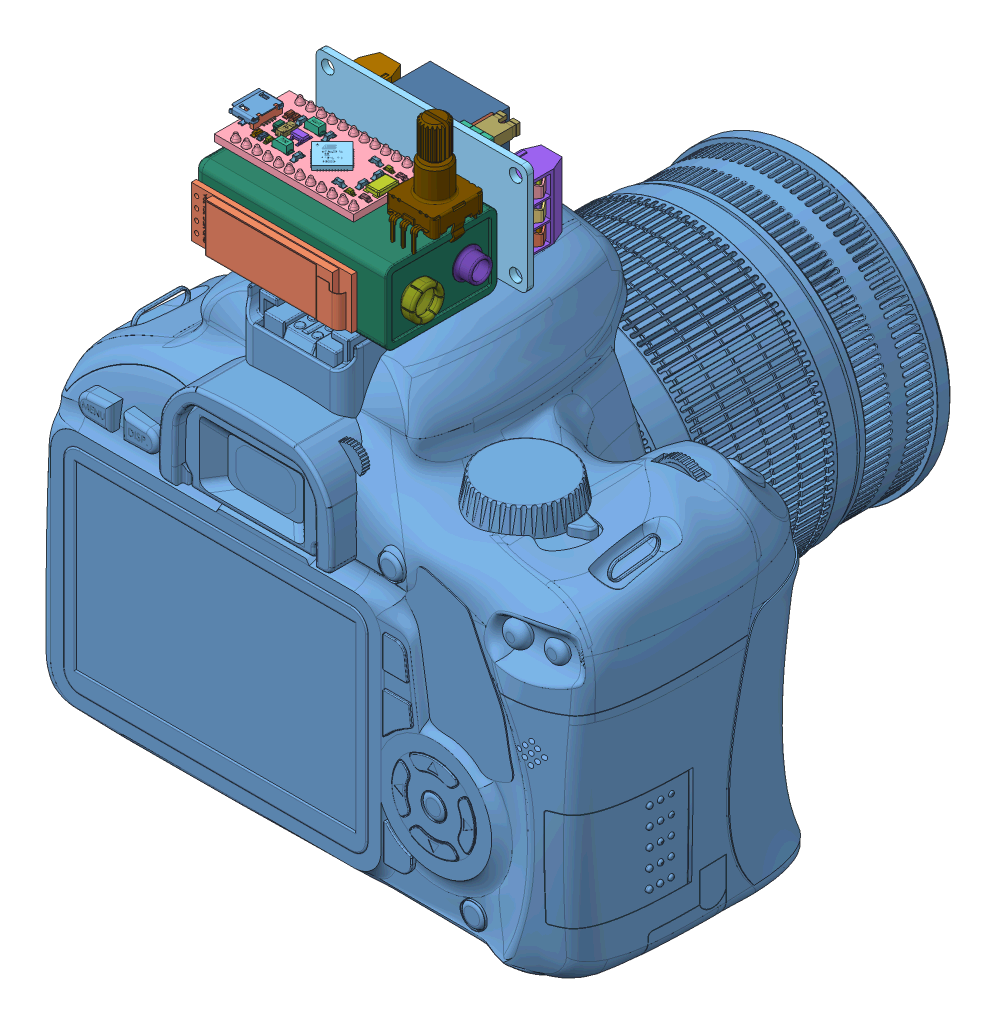
SolidWorks assembly Intervalometer_V1, configuration Default. Lengths in mm.
Overall size (132.46 153.58 139.83).
93 component instances, 74 part files, 0 mates.
Components (placement in the parent):
- ARDUINO PRO MICRO^Intervalometer_V1-1: ARDUINO PRO MICRO^Intervalometer_V1 [Default] at (-2.2476 67.1806 24.4851) size (34.59 4.25 17.78) (virtual)
  - micro usb^ARDUINO PRO MICRO_Intervalometer_V1-1: micro usb^ARDUINO PRO MICRO_Intervalometer_V1 [Default] at (-4.75 1.85 -7.62) x (0 0 1) z (-1 0 0) size (8 3.25 5.93) (virtual)
    - micro usb shell^micro usb_ARDUINO PRO MICRO_Intervalometer_V1-1: micro usb shell^micro usb_ARDUINO PRO MICRO_Intervalometer_V1 [Default] at origin size (8 2.95 5.63) (virtual)
    - micro usb internal^micro usb_ARDUINO PRO MICRO_Intervalometer_V1-1: micro usb internal^micro usb_ARDUINO PRO MICRO_Intervalometer_V1 [Default] at (0 -0.25 0) size (6.9 2.9 4) (virtual)
    - micro usb contact^micro usb_ARDUINO PRO MICRO_Intervalometer_V1-1: micro usb contact^micro usb_ARDUINO PRO MICRO_Intervalometer_V1 [Default] at (1.3 -0.25 -0.1) size (0.2 1.3 4.4) (virtual)
    - micro usb contact^micro usb_ARDUINO PRO MICRO_Intervalometer_V1-2: micro usb contact^micro usb_ARDUINO PRO MICRO_Intervalometer_V1 [Default] at (0.65 -0.25 -0.1) size (0.2 1.3 4.4) (virtual)
    - micro usb contact^micro usb_ARDUINO PRO MICRO_Intervalometer_V1-3: micro usb contact^micro usb_ARDUINO PRO MICRO_Intervalometer_V1 [Default] at (0 -0.25 -0.1) size (0.2 1.3 4.4) (virtual)
    - micro usb contact^micro usb_ARDUINO PRO MICRO_Intervalometer_V1-4: micro usb contact^micro usb_ARDUINO PRO MICRO_Intervalometer_V1 [Default] at (-0.65 -0.25 -0.1) size (0.2 1.3 4.4) (virtual)
    - micro usb contact^micro usb_ARDUINO PRO MICRO_Intervalometer_V1-5: micro usb contact^micro usb_ARDUINO PRO MICRO_Intervalometer_V1 [Default] at (-1.3 -0.25 -0.1) size (0.2 1.3 4.4) (virtual)
  - micro board^ARDUINO PRO MICRO_Intervalometer_V1-1: micro board^ARDUINO PRO MICRO_Intervalometer_V1 [Default] at origin size (33.02 3.1 17.78) (virtual)
  - atmega32U4^ARDUINO PRO MICRO_Intervalometer_V1-1: atmega32U4^ARDUINO PRO MICRO_Intervalometer_V1 [Default] at (15.24 1.62 -7.62) x (-0.707107 0 0.707107) z (-0.707107 0 -0.707107) size (7.23 1.02 7.23) (virtual)
  - MICRO_cap106C^ARDUINO PRO MICRO_Intervalometer_V1-1: MICRO_cap106C^ARDUINO PRO MICRO_Intervalometer_V1 [Default] at (7.3558 1.6 -11.4427) x (0 0 -1) z (1 0 0) size (1.7 1.81 4) (virtual)
  - MICRO_cap106C^ARDUINO PRO MICRO_Intervalometer_V1-2: MICRO_cap106C^ARDUINO PRO MICRO_Intervalometer_V1 [Default] at (7.3558 1.6 -3.7973) x (0 0 -1) z (1 0 0) size (1.7 1.81 4) (virtual)
  - micro_crystal 5x3^ARDUINO PRO MICRO_Intervalometer_V1-1: micro_crystal 5x3^ARDUINO PRO MICRO_Intervalometer_V1 [Default] at (27.051 1.65 -7.62) x (0 0 -1) z (1 0 0) size (5.7 1 3.4) (virtual)
  - micro_MIC5219^ARDUINO PRO MICRO_Intervalometer_V1-1: micro_MIC5219^ARDUINO PRO MICRO_Intervalometer_V1 [Default] at (7.366 1.6 -7.874) x (-1 0 0) z (0 0 -1) size (2.9 1.2 3.68) (virtual)
  - MICRO_603 resistor 103^ARDUINO PRO MICRO_Intervalometer_V1-1: MICRO_603 resistor 103^ARDUINO PRO MICRO_Intervalometer_V1 [Default] at (1.27 1.6 -3.81) x (0 0 1) z (-1 0 0) size (2.36 0.61 1.02) (virtual)
  - MICRO_603 resistor 102^ARDUINO PRO MICRO_Intervalometer_V1-1: MICRO_603 resistor 102^ARDUINO PRO MICRO_Intervalometer_V1 [Default] at (2.667 1.6 -3.81) x (0 0 1) z (-1 0 0) size (2.36 0.61 1.02) (virtual)
  - MICRO_603 resistor 22^ARDUINO PRO MICRO_Intervalometer_V1-1: MICRO_603 resistor 22^ARDUINO PRO MICRO_Intervalometer_V1 [Default] at (1.27 1.6 -11.43) x (0 0 1) z (-1 0 0) size (2.36 0.61 1.02) (virtual)
  - MICRO_603 resistor 22^ARDUINO PRO MICRO_Intervalometer_V1-2: MICRO_603 resistor 22^ARDUINO PRO MICRO_Intervalometer_V1 [Default] at (2.667 1.6 -11.43) x (0 0 1) z (-1 0 0) size (2.36 0.61 1.02) (virtual)
  - MICRO_PTC-1206^ARDUINO PRO MICRO_Intervalometer_V1-1: MICRO_PTC-1206^ARDUINO PRO MICRO_Intervalometer_V1 [Default] at (4.445 1.6 -7.62) x (0 0 1) z (-1 0 0) size (3.85 1.17 1.82) (virtual)
  - MICRO_603 resistor 331^ARDUINO PRO MICRO_Intervalometer_V1-1: MICRO_603 resistor 331^ARDUINO PRO MICRO_Intervalometer_V1 [Default] at (27.432 1.6 -11.938) size (2.36 0.61 1.02) (virtual)
  - MICRO_603 resistor 331^ARDUINO PRO MICRO_Intervalometer_V1-2: MICRO_603 resistor 331^ARDUINO PRO MICRO_Intervalometer_V1 [Default] at (27.432 1.6 -3.302) size (2.36 0.61 1.02) (virtual)
  - MICRO_603 cap on pad^ARDUINO PRO MICRO_Intervalometer_V1-1: MICRO_603 cap on pad^ARDUINO PRO MICRO_Intervalometer_V1 [Default] at (24.384 1.6 -9.398) x (0 0 1) z (-1 0 0) size (2.76 0.9 1.03) (virtual)
  - MICRO_603 cap on pad^ARDUINO PRO MICRO_Intervalometer_V1-2: MICRO_603 cap on pad^ARDUINO PRO MICRO_Intervalometer_V1 [Default] at (21.336 1.6 -11.938) size (2.76 0.9 1.03) (virtual)
  - MICRO_603 cap on pad^ARDUINO PRO MICRO_Intervalometer_V1-3: MICRO_603 cap on pad^ARDUINO PRO MICRO_Intervalometer_V1 [Default] at (24.384 1.6 -5.715) x (0 0 1) z (-1 0 0) size (2.76 0.9 1.03) (virtual)
  - MICRO_603 cap on pad^ARDUINO PRO MICRO_Intervalometer_V1-4: MICRO_603 cap on pad^ARDUINO PRO MICRO_Intervalometer_V1 [Default] at (21.336 1.6 -3.1877) size (2.76 0.9 1.03) (virtual)
  - MICRO_603 cap on pad^ARDUINO PRO MICRO_Intervalometer_V1-5: MICRO_603 cap on pad^ARDUINO PRO MICRO_Intervalometer_V1 [Default] at (11.0744 1.6 -3.5839) x (0 0 -1) z (1 0 0) size (2.76 0.9 1.03) (virtual)
  - MICRO_603 cap on pad^ARDUINO PRO MICRO_Intervalometer_V1-6: MICRO_603 cap on pad^ARDUINO PRO MICRO_Intervalometer_V1 [Default] at (10.6528 1.6 -11.4681) x (0 0 1) z (-1 0 0) size (2.76 0.9 1.03) (virtual)
  - MICRO_603 cap on pad^ARDUINO PRO MICRO_Intervalometer_V1-7: MICRO_603 cap on pad^ARDUINO PRO MICRO_Intervalometer_V1 [Default] at (4.1758 1.6 -11.43) x (0 0 -1) z (1 0 0) size (2.76 0.9 1.03) (virtual)
  - SOD 323^ARDUINO PRO MICRO_Intervalometer_V1-1: SOD 323^ARDUINO PRO MICRO_Intervalometer_V1 [Default] at (2.6416 1.6 -7.62) x (0 0 1) z (-1 0 0) size (2.94 1.1 1.25) (virtual)
  - MICRO_led^ARDUINO PRO MICRO_Intervalometer_V1-1: MICRO_led^ARDUINO PRO MICRO_Intervalometer_V1 [Default] at (24.384 1.62 -2.6907) size (2.3 0.72 0.8) (virtual)
  - MICRO_led^ARDUINO PRO MICRO_Intervalometer_V1-2: MICRO_led^ARDUINO PRO MICRO_Intervalometer_V1 [Default] at (24.384 1.62 -11.938) size (2.3 0.72 0.8) (virtual)
  - MICRO_led^ARDUINO PRO MICRO_Intervalometer_V1-3: MICRO_led^ARDUINO PRO MICRO_Intervalometer_V1 [Default] at (4.1046 1.62 -3.81) x (0 0 -1) z (1 0 0) size (2.3 0.72 0.8) (virtual)
- HW-803_Ralay^Intervalometer_V1-1: HW-803_Ralay^Intervalometer_V1 [Default] at (-6.3036 48.3228 1.3744) x (1 0 0) z (0 1 0) size (50 16.43 26) (virtual)
  - Component1^HW-803_Ralay_Intervalometer_V1-1: Component1^HW-803_Ralay_Intervalometer_V1 [Default] at (3.584 7.2449 6.3576) x (0 1 0) z (0 0 1) size (4.68 2.37 3.3) (virtual)
  - Component2^HW-803_Ralay_Intervalometer_V1-1: Component2^HW-803_Ralay_Intervalometer_V1 [Default] at (3.584 7.2449 11.2576) x (0 1 0) z (0 0 1) size (4.68 2.37 3.3) (virtual)
  - Component3^HW-803_Ralay_Intervalometer_V1-1: Component3^HW-803_Ralay_Intervalometer_V1 [Default] at (3.584 7.2449 16.1576) x (0 1 0) z (0 0 1) size (4.68 2.37 3.3) (virtual)
  - Component5^HW-803_Ralay_Intervalometer_V1-1: Component5^HW-803_Ralay_Intervalometer_V1 [Default] at (46.1075 7.2449 9.6576) x (0 1 0) z (0 0 -1) size (4.68 2.37 3.3) (virtual)
  - Component6^HW-803_Ralay_Intervalometer_V1-1: Component6^HW-803_Ralay_Intervalometer_V1 [Default] at (46.1075 7.2449 14.5576) x (0 1 0) z (0 0 -1) size (4.68 2.37 3.3) (virtual)
  - Component7^HW-803_Ralay_Intervalometer_V1-1: Component7^HW-803_Ralay_Intervalometer_V1 [Default] at (46.1075 7.2449 19.5076) x (0 1 0) z (0 0 -1) size (4.68 2.37 3.3) (virtual)
  - Relay Switch^HW-803_Ralay_Intervalometer_V1-1: Relay Switch^HW-803_Ralay_Intervalometer_V1 [Default] at origin size (50 1.5 26) (virtual)
  - Relay Switch-0^HW-803_Ralay_Intervalometer_V1-1: Relay Switch-0^HW-803_Ralay_Intervalometer_V1 [Default] at origin size (7.3 2 2.5) (virtual)
  - Relay Switch-1^HW-803_Ralay_Intervalometer_V1-1: Relay Switch-1^HW-803_Ralay_Intervalometer_V1 [Default] at origin size (3.82 1.5 3.82) (virtual)
  - Relay Switch-2^HW-803_Ralay_Intervalometer_V1-1: Relay Switch-2^HW-803_Ralay_Intervalometer_V1 [Default] at origin size (7.77 10.32 15.62) (virtual)
  - Relay Switch-3^HW-803_Ralay_Intervalometer_V1-1: Relay Switch-3^HW-803_Ralay_Intervalometer_V1 [Default] at origin size (7.77 10.48 15.35) (virtual)
  - Relay Switch-4^HW-803_Ralay_Intervalometer_V1-1: Relay Switch-4^HW-803_Ralay_Intervalometer_V1 [Default] at origin size (18.85 14.93 14.91) (virtual)
  - Relay Switch-5^HW-803_Ralay_Intervalometer_V1-1: Relay Switch-5^HW-803_Ralay_Intervalometer_V1 [Default] at origin size (0.65 6 0.58) (virtual)
  - Relay Switch-6^HW-803_Ralay_Intervalometer_V1-1: Relay Switch-6^HW-803_Ralay_Intervalometer_V1 [Default] at origin size (4.8 6.2 2.52) (virtual)
  - Relay Switch-7^HW-803_Ralay_Intervalometer_V1-1: Relay Switch-7^HW-803_Ralay_Intervalometer_V1 [Default] at origin size (0.6 1.6 0.6) (virtual)
  - Relay Switch-8^HW-803_Ralay_Intervalometer_V1-1: Relay Switch-8^HW-803_Ralay_Intervalometer_V1 [Default] at origin size (0.6 1.6 0.6) (virtual)
  - Relay Switch-9^HW-803_Ralay_Intervalometer_V1-1: Relay Switch-9^HW-803_Ralay_Intervalometer_V1 [Default] at origin size (3 0.7 0.09) (virtual)
  - Relay Switch-10^HW-803_Ralay_Intervalometer_V1-1: Relay Switch-10^HW-803_Ralay_Intervalometer_V1 [Default] at origin size (3.7 1 3.7) (virtual)
  - Relay Switch-11^HW-803_Ralay_Intervalometer_V1-1: Relay Switch-11^HW-803_Ralay_Intervalometer_V1 [Default] at origin size (3.7 1 3.7) (virtual)
  - Relay Switch-12^HW-803_Ralay_Intervalometer_V1-1: Relay Switch-12^HW-803_Ralay_Intervalometer_V1 [Default] at origin size (3.7 1 3.7) (virtual)
  - Relay Switch-13^HW-803_Ralay_Intervalometer_V1-1: Relay Switch-13^HW-803_Ralay_Intervalometer_V1 [Default] at origin size (3.7 1 3.7) (virtual)
  - Relay Switch-14^HW-803_Ralay_Intervalometer_V1-1: Relay Switch-14^HW-803_Ralay_Intervalometer_V1 [Default] at origin size (3.7 1 3.7) (virtual)
  - Relay Switch-15^HW-803_Ralay_Intervalometer_V1-1: Relay Switch-15^HW-803_Ralay_Intervalometer_V1 [Default] at origin size (3.7 1 3.7) (virtual)
  - Relay Switch-16^HW-803_Ralay_Intervalometer_V1-1: Relay Switch-16^HW-803_Ralay_Intervalometer_V1 [Default] at origin size (1 5 4.3) (virtual)
  - Relay Switch-17^HW-803_Ralay_Intervalometer_V1-1: Relay Switch-17^HW-803_Ralay_Intervalometer_V1 [Default] at origin size (1 5 4.3) (virtual)
  - Relay Switch-18^HW-803_Ralay_Intervalometer_V1-1: Relay Switch-18^HW-803_Ralay_Intervalometer_V1 [Default] at origin size (1 5 4.3) (virtual)
  - Relay Switch-19^HW-803_Ralay_Intervalometer_V1-1: Relay Switch-19^HW-803_Ralay_Intervalometer_V1 [Default] at origin size (1 5 4.3) (virtual)
  - Relay Switch-20^HW-803_Ralay_Intervalometer_V1-1: Relay Switch-20^HW-803_Ralay_Intervalometer_V1 [Default] at origin size (1 5 4.3) (virtual)
  - Relay Switch-21^HW-803_Ralay_Intervalometer_V1-1: Relay Switch-21^HW-803_Ralay_Intervalometer_V1 [Default] at origin size (1 5 4.3) (virtual)
  - Relay Switch-22^HW-803_Ralay_Intervalometer_V1-1: Relay Switch-22^HW-803_Ralay_Intervalometer_V1 [Default] at origin size (1.3 1.2 0.7) (virtual)
  - Relay Switch-23^HW-803_Ralay_Intervalometer_V1-1: Relay Switch-23^HW-803_Ralay_Intervalometer_V1 [Default] at origin size (1.3 1.2 0.7) (virtual)
  - Relay Switch-24^HW-803_Ralay_Intervalometer_V1-1: Relay Switch-24^HW-803_Ralay_Intervalometer_V1 [Default] at origin size (1.3 1.2 0.7) (virtual)
  - Relay Switch-25^HW-803_Ralay_Intervalometer_V1-1: Relay Switch-25^HW-803_Ralay_Intervalometer_V1 [Default] at origin size (1.3 1.2 0.7) (virtual)
  - Relay Switch-26^HW-803_Ralay_Intervalometer_V1-1: Relay Switch-26^HW-803_Ralay_Intervalometer_V1 [Default] at origin size (1.09 0.4 2) (virtual)
  - Relay Switch-27^HW-803_Ralay_Intervalometer_V1-1: Relay Switch-27^HW-803_Ralay_Intervalometer_V1 [Default] at origin size (1.09 0.4 2) (virtual)
  - Relay Switch-28^HW-803_Ralay_Intervalometer_V1-1: Relay Switch-28^HW-803_Ralay_Intervalometer_V1 [Default] at origin size (1.09 0.4 2) (virtual)
  - Relay Switch-29^HW-803_Ralay_Intervalometer_V1-1: Relay Switch-29^HW-803_Ralay_Intervalometer_V1 [Default] at origin size (2 0.4 1.09) (virtual)
  - Relay Switch-30^HW-803_Ralay_Intervalometer_V1-1: Relay Switch-30^HW-803_Ralay_Intervalometer_V1 [Default] at origin size (1.09 0.4 2) (virtual)
  - Relay Switch-31^HW-803_Ralay_Intervalometer_V1-1: Relay Switch-31^HW-803_Ralay_Intervalometer_V1 [Default] at origin size (1.09 0.3 1.5) (virtual)
  - Relay Switch-32^HW-803_Ralay_Intervalometer_V1-1: Relay Switch-32^HW-803_Ralay_Intervalometer_V1 [Default] at origin size (1.09 0.3 1.5) (virtual)
  - Relay Switch-33^HW-803_Ralay_Intervalometer_V1-1: Relay Switch-33^HW-803_Ralay_Intervalometer_V1 [Default] at origin size (1.09 0.3 1.5) (virtual)
  - Relay Switch-34^HW-803_Ralay_Intervalometer_V1-1: Relay Switch-34^HW-803_Ralay_Intervalometer_V1 [Default] at origin size (1.09 0.3 1.5) (virtual)
  - Relay Switch-35^HW-803_Ralay_Intervalometer_V1-1: Relay Switch-35^HW-803_Ralay_Intervalometer_V1 [Default] at origin size (1.5 0.3 1.09) (virtual)
  - Relay Switch-36^HW-803_Ralay_Intervalometer_V1-1: Relay Switch-36^HW-803_Ralay_Intervalometer_V1 [Default] at origin size (2.65 1.2 1.3) (virtual)
  - Relay Switch-37^HW-803_Ralay_Intervalometer_V1-1: Relay Switch-37^HW-803_Ralay_Intervalometer_V1 [Default] at origin size (2 0.6 1.28) (virtual)
  - Relay Switch-38^HW-803_Ralay_Intervalometer_V1-1: Relay Switch-38^HW-803_Ralay_Intervalometer_V1 [Default] at origin size (1.28 0.6 2) (virtual)
  - Relay Switch-39^HW-803_Ralay_Intervalometer_V1-1: Relay Switch-39^HW-803_Ralay_Intervalometer_V1 [Default] at origin size (0.5 1.1 0.55) (virtual)
  - Relay Switch-40^HW-803_Ralay_Intervalometer_V1-1: Relay Switch-40^HW-803_Ralay_Intervalometer_V1 [Default] at origin size (0.5 1.1 0.55) (virtual)
  - Relay Switch-41^HW-803_Ralay_Intervalometer_V1-1: Relay Switch-41^HW-803_Ralay_Intervalometer_V1 [Default] at origin size (0.5 1.1 0.55) (virtual)
  - Relay Switch-42^HW-803_Ralay_Intervalometer_V1-1: Relay Switch-42^HW-803_Ralay_Intervalometer_V1 [Default] at origin size (1.43 1.43 0.4) (virtual)
  - Relay Switch-43^HW-803_Ralay_Intervalometer_V1-1: Relay Switch-43^HW-803_Ralay_Intervalometer_V1 [Default] at origin size (1.15 1.15 2.4) (virtual)
  - Relay Switch-44^HW-803_Ralay_Intervalometer_V1-1: Relay Switch-44^HW-803_Ralay_Intervalometer_V1 [Default] at origin size (1.43 1.43 0.4) (virtual)
- 9V_Batterie(2)^Intervalometer_V1-1: 9V_Batterie(2)^Intervalometer_V1 [Default] at (39.5559 57.5396 17.5194) x (0 0 -1) z (-1 0 0) size (26.5 17.5 49.69) (virtual)
  - Corps Batterie^9V_Batterie(2)_Intervalometer_V1-1: Corps Batterie^9V_Batterie(2)_Intervalometer_V1 [Default] at origin size (26.5 17.5 45.5) (virtual)
  - Connecteur femelle Batterie 9V^9V_Batterie(2)_Intervalometer_V1-1: Connecteur femelle Batterie 9V^9V_Batterie(2)_Intervalometer_V1 [Default] at (-6.5 0 0.5) x (1 0 0) z (0 1 0) size (8.01 5.32 8.38) (virtual)
  - Connecteur male Batterie 9V^9V_Batterie(2)_Intervalometer_V1-1: Connecteur male Batterie 9V^9V_Batterie(2)_Intervalometer_V1 [Default] at (6.5 0 0.5) x (0.847736 0.530419 0) z (-0.530419 0.847736 0) size (7.01 4.82 7.01) (virtual)
- EC11 Rotary Encoder Dode Switch-15mm ^Intervalometer_V1-1: EC11 Rotary Encoder Dode Switch-15mm ^Intervalometer_V1 [Default] at (37.899 70.6065 17.4555) x (1 0 0) z (0 1 0) size (11.71 14.96 23.16) (virtual)
- DSLR-1: DSLR [Default] at (94.4302 -53.142 -35.5835) x (-1 0 0) z (0 0 -1) size (132.46 109.09 139.83)
- 128x32-OLED-2: 128x32-OLED [Default] at (15.1846 57.8401 32.2482) size (38 12 2.96)
